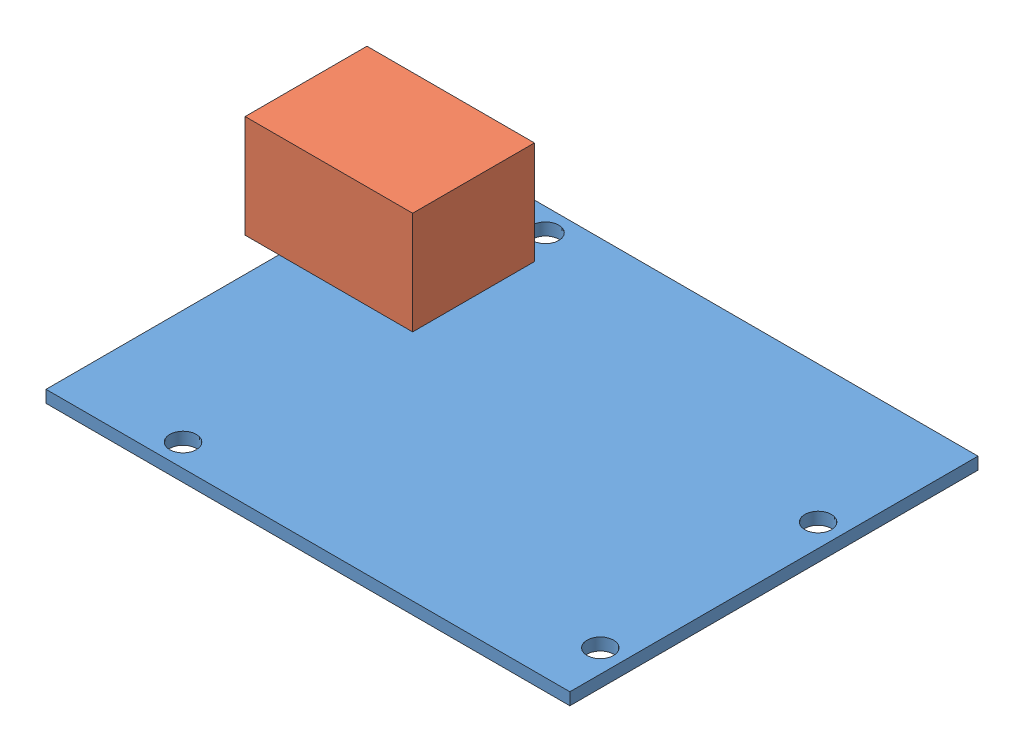
SolidWorks assembly Arduino, configuration Default. Lengths in mm.
Overall size (73.25 15.1 53.6).
2 component instances, 2 part files, 3 mates.
Components (placement in the parent):
- Arduino-1: Arduino [Default] at origin size (68.8 1.6 53.6)
- Part11^Arduino-1: Part11^Arduino [Default] at (19.5866 0 7.8826) size (22 13.5 16) (virtual)
Mates (geometry in assembly coordinates):
- Coincident1: coincident anti-aligned: plane of Arduino-1 through (-34.4 1.6 -26.8) normal (0 1 0); plane of Part11^Arduino-1 through (-16.85 1.6 -3.8) normal (0 -1 0)
- Distance1: distance = 7 mm aligned: plane of Part11^Arduino-1 through (-38.85 15.1 -19.8) normal (0 0 -1); plane of Arduino-1 through (34.4 1.6 -26.8) normal (0 0 -1)
- Distance2: distance = 4.45 mm aligned: plane of Part11^Arduino-1 through (-38.85 15.1 -19.8) normal (-1 0 0); plane of Arduino-1 through (-34.4 1.6 26.8) normal (-1 0 0)
